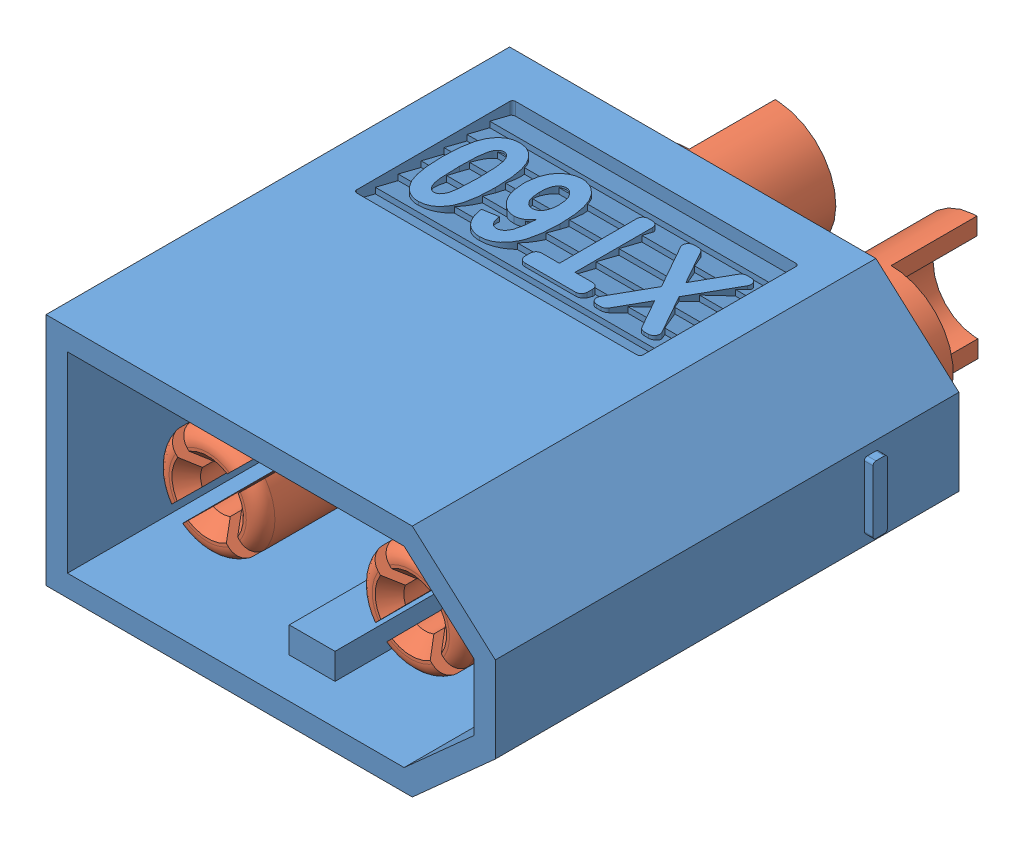
SolidWorks assembly XT-60_Macho 1, configuration Valor predeterminado. Lengths in mm.
Overall size (16.3 8.2 28.2).
3 component instances, 2 part files, 7 mates.
Components (placement in the parent):
- XT-60_Macho-1: XT-60_Macho [Valor predeterminado] at (-37.9952 28.536 -8.1) size (16.3 8.2 16.2)
- PinoXT-60_Macho-1: PinoXT-60_Macho [Valor predeterminado] at (-26.6452 32.636 -13.1) x (-0.008124 0.999967 0) z (0.999967 0.008124 0) size (4.3 26.83 4.3)
- PinoXT-60_Macho-2: PinoXT-60_Macho [Valor predeterminado] at (-33.7452 32.636 -13.1) x (-0.014321 -0.999897 0) z (-0.999897 0.014321 0) size (4.3 26.83 4.3)
Mates (geometry in assembly coordinates):
- Concêntrico1: concentric aligned: cylinder of XT-60_Macho-1 through (-26.6452 32.636 8.1) axis (0 0 -1) radius 2.15; cylinder of PinoXT-60_Macho-1 through (-26.6452 32.636 -3.1) axis (0 0 -1) radius 2.15
- Concêntrico2: concentric aligned: cylinder of XT-60_Macho-1 through (-33.7452 32.636 8.1) axis (0 0 -1) radius 2.15; cylinder of PinoXT-60_Macho-2 through (-33.7452 32.636 -3.1) axis (0 0 -1) radius 2.15
- Distância1: distance = 1.4 mm aligned: plane of PinoXT-60_Macho-1 through (-26.6627 34.786 6.7) normal (0 0 1); plane of XT-60_Macho-1 through (-37.9952 28.536 8.1) normal (0 0 1)
- Distância2: distance = 1.4 mm aligned: plane of PinoXT-60_Macho-2 through (-33.776 30.4863 6.7) normal (0 0 1); plane of XT-60_Macho-1 through (-37.9952 28.536 8.1) normal (0 0 1)
- LimitDistance1: limit distance = 0 mm anti-aligned: plane of ? through (-37.9952 38.536 8.1) normal (0 0 -1); plane of XT-60_Macho-1 through (-37.9952 28.536 8.1) normal (0 0 1)
- Width1: width aligned: plane of XT-60_Macho-1 through (-23.0452 31.4709 -1.3) normal (-1 0 0); plane of XT-60_Macho-1 through (-37.2452 35.986 -1.3) normal (1 0 0); plane of ? through (-37.1952 29.336 0.4) normal (-1 0 0); plane of ? through (-23.0952 33.7788 0.4) normal (1 0 0)
- Width2: width aligned: plane of ? through (-37.1952 35.936 0.4) normal (0 1 0); plane of ? through (-25.5014 29.336 0.4) normal (0 -1 0); plane of XT-60_Macho-1 through (-37.2452 29.286 -1.3) normal (0 1 0); plane of XT-60_Macho-1 through (-25.4822 35.986 -1.3) normal (0 -1 0)
